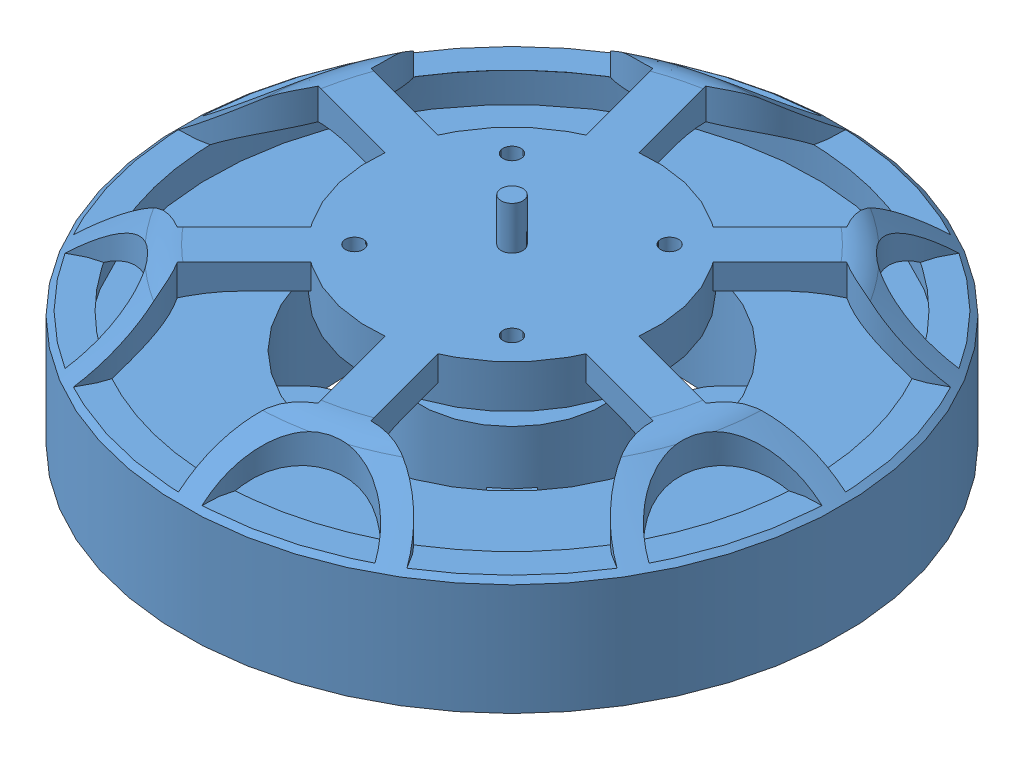
SolidWorks assembly Motor Assem, configuration Default. Lengths in mm.
Overall size (129.63 44.53 129.63).
4 component instances, 4 part files, 10 mates.
Components (placement in the parent):
- 9225 160kv-1: 9225 160kv [Default] at (0 -18.055 0) x (0.707107 0 0.707107) z (-0.707107 0 0.707107) size (91.66 44.53 91.66)
- Encoder Magnet-1: Encoder Magnet [Default] at (0 -19.6425 0) size (6.35 3.17 6.35)
- Magnut hex puck-1: Magnut hex puck [Default] at (0 -18.055 0) x (0.707107 0 0.707107) z (-0.707107 0 0.707107) size (22.91 4.76 22.91)
- encoder final board-1: encoder final board [Default] at (0 -23.0237 0) x (0 0 -1) z (1 0 0) size (25 2.95 25)
Mates (geometry in assembly coordinates):
- Coincident6: coincident anti-aligned: plane of 9225 160kv-1 through (0 -18.055 0) normal (0 -1 0); circle of Encoder Magnet-1
- Concentric2: concentric aligned: cylinder of Encoder Magnet-1 through (0 -18.055 0) axis (0 -1 0) radius 3.175
- Coincident7: coincident aligned: plane of Encoder Magnet-1 through (0 -19.6425 0) normal (0 0 1)
- Concentric4: concentric anti-aligned: cylinder of 9225 160kv-1 through (0 20.125 0) axis (0 1 0) radius 45.83
- Parallel2: parallel anti-aligned: plane of 9225 160kv-1 through (-3.25 -24.405 -36.33) normal (0 0 -1)
- Symmetric1: symmetric aligned: plane of 9225 160kv-1 through (22.981 14.125 22.981) normal (0 1 0); plane of 9225 160kv-1 through (6.8236 -14.125 6.8236) normal (0 -1 0)
- Coincident17: coordinate: point of 9225 160kv-1; point of Magnut hex puck-1
- Coincident24: coincident aligned: plane of encoder final board-1 through (0 -23.0237 0) normal (1 0 0)
- Distance1: distance = 0.7937 mm anti-aligned: plane of encoder final board-1 through (0 -22.0238 0) normal (0 1 0); plane of Encoder Magnet-1 through (0 -21.23 0) normal (0 -1 0)
- Coincident25: coincident: unknown of encoder final board-1
